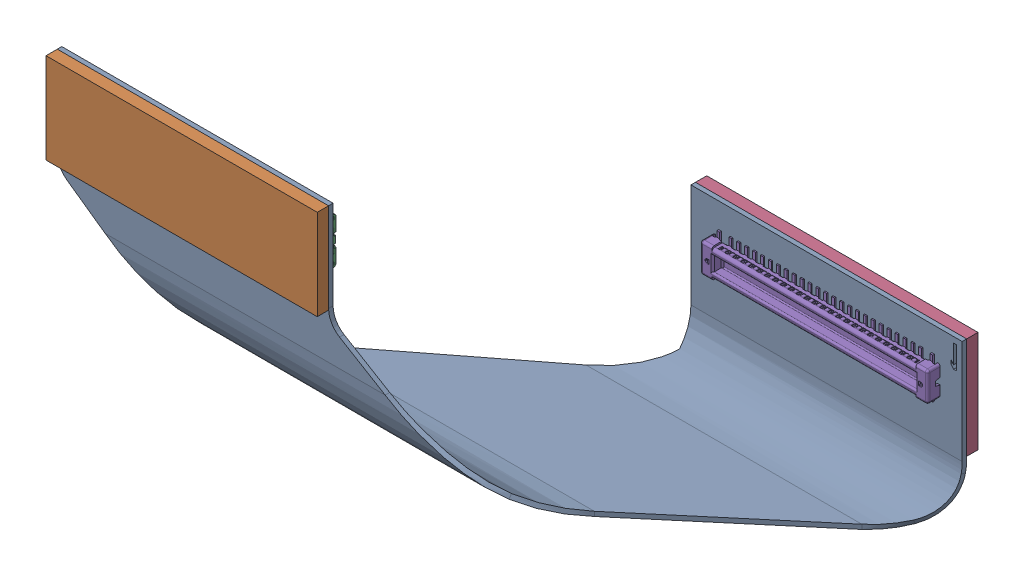
SolidWorks assembly FPC_DS5_DK_ASIC_AWG_STEREO_IM_1_ASM, configuration Default. Lengths in mm.
Overall size (29.07 9.25 12.16).
5 component instances, 5 part files, 0 mates.
Components (placement in the parent):
- AWG_ASIC_FLEX_33-1: AWG_ASIC_FLEX_33 [Default] at origin size (29.07 9.25 11.16)
- AWG_ASIC_BACKER_1_77-1: AWG_ASIC_BACKER_1_77 [Default] at (0 0 0.2) size (12 4 0.5)
- ID_50_PIN_20709-050EC_PAD_4-1: ID_50_PIN_20709-050EC_PAD_4 [Default] at (2.68 -3.605 -9.31) x (1 0 0) z (0 0 -1) size (10.92 2.3 0.67)
- AWG_ASIC_BACKER_2_84-1: AWG_ASIC_BACKER_2_84 [Default] at (0 0 -0.2) size (12 4.5 0.5)
- 20708-050E_PLUG_ASSY_3-1: 20708-050E_PLUG_ASSY_3 [Default] at (23.95 -5.75 -19.37) x (1 0 0) z (0 1 0) size (10.06 0.56 1.8)
